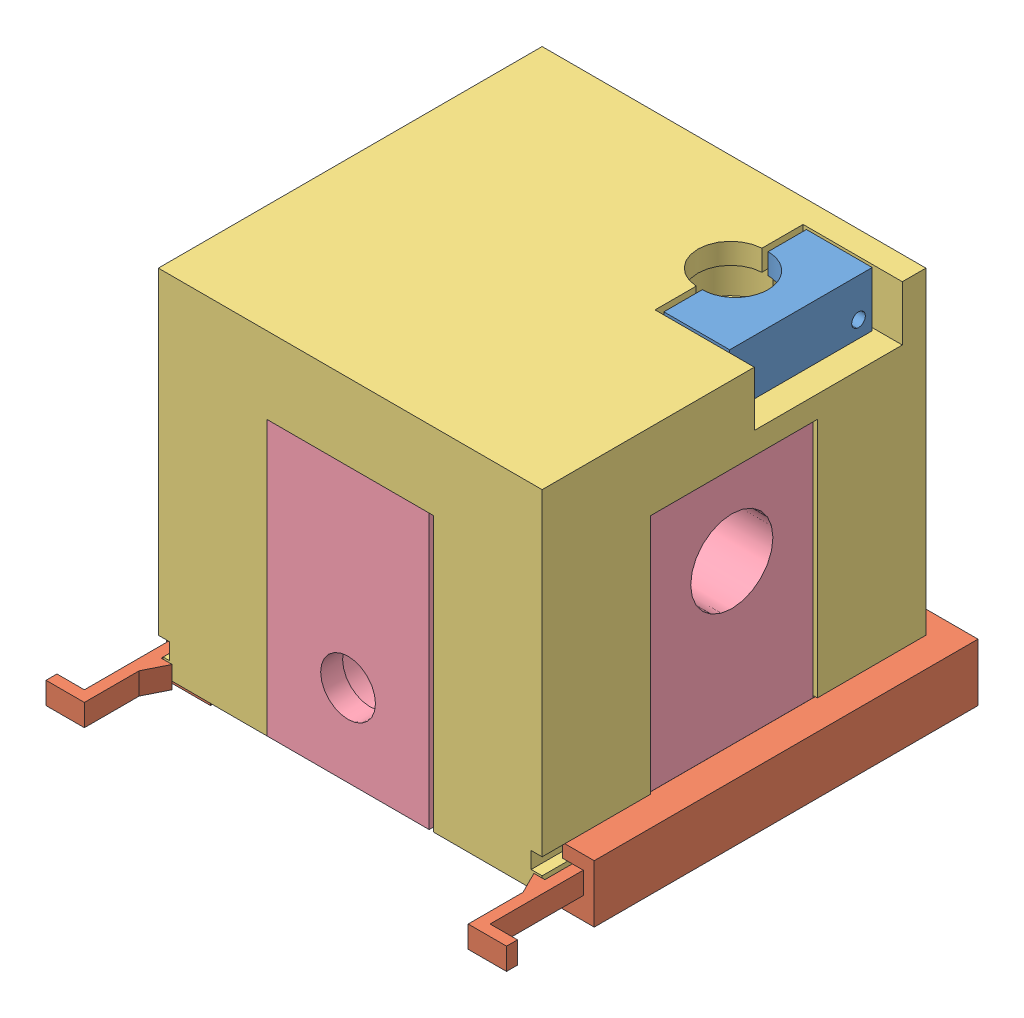
SolidWorks assembly P3DMIPC-Tête_complete, configuration Défaut. Lengths in mm.
Overall size (84 69 89).
4 component instances, 4 part files, 3 mates.
Components (placement in the parent):
- P3DMIPC-Clip_Buse_E3D-1: P3DMIPC-Clip_Buse_E3D [Défaut] at (17.0518 23.4109 40.0035) x (1 0 0) z (0 1 0) size (12 26 10)
- P3DMIPC-Clip_tête-1: P3DMIPC-Clip_tête [Défaut] at (26.9018 -25.0891 4.5597) x (1 0 0) z (0 -1 0) size (84 89 10.5)
- P3DMIPC-Porte_Buse_E3DX1-1: P3DMIPC-Porte_Buse_E3DX1 [Défaut] at (22.03 33.4019 79.1927) x (0 0 1) z (0 -1 0) size (70 70 64)
- P3DMIPC-Chariot-1: P3DMIPC-Chariot [Défaut] at (-48.37 -30.5981 79.1927) size (70 50 70)
Mates (geometry in assembly coordinates):
- Coïncidente19: coincident anti-aligned: plane of P3DMIPC-Porte_Buse_E3DX1-1 through (22.03 19.4019 79.1927) normal (0 -1 0); plane of P3DMIPC-Chariot-1 through (21.63 19.4019 79.1927) normal (0 1 0)
- Coïncidente20: coincident anti-aligned: plane of P3DMIPC-Porte_Buse_E3DX1-1 through (-28.17 19.4019 79.1927) normal (1 0 0); plane of P3DMIPC-Chariot-1 through (-28.17 19.4019 79.1927) normal (-1 0 0)
- Coïncidente21: coincident aligned: plane of P3DMIPC-Porte_Buse_E3DX1-1 through (22.03 -30.5981 79.1927) normal (0 0 1); plane of P3DMIPC-Chariot-1 through (21.63 -30.5981 79.1927) normal (0 0 1)
